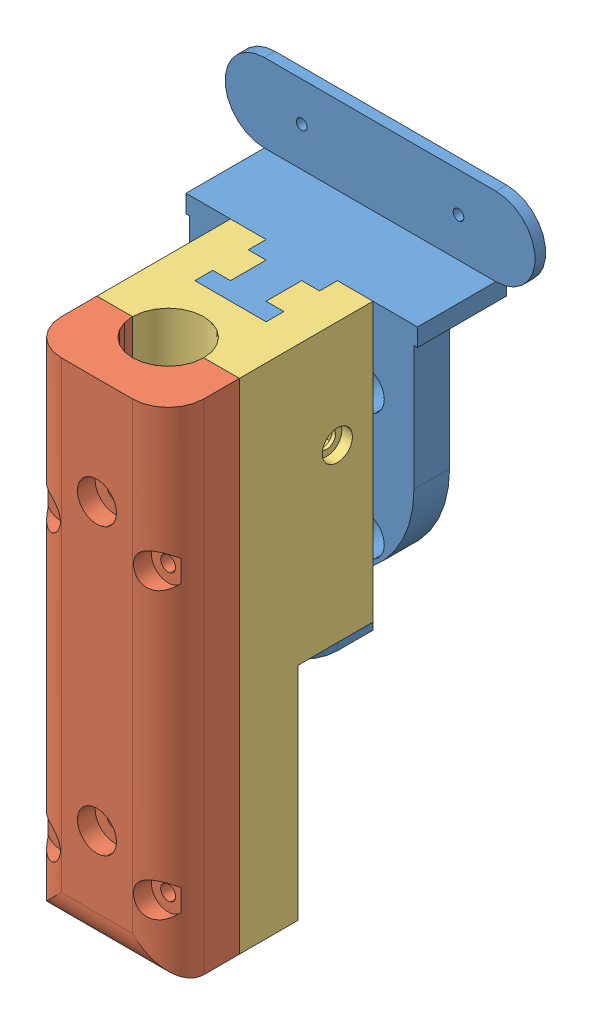
SolidWorks assembly Assem1, configuration Default. Lengths in mm.
Overall size (87 162 82.5).
3 component instances, 3 part files, 6 mates.
Components (placement in the parent):
- cameramountv3-2: cameramountv3 [Default] at (27.1037 71.5301 71.6492) size (87 102 45)
- lidmarkholder-2: lidmarkholder [Default] at (27.1037 41.5301 119.1492) size (40 140 20)
- markholderv1-2: markholderv1 [Default] at (27.1037 111.5301 81.6492) size (40 140 37.5)
Mates (geometry in assembly coordinates):
- Coincident1: coincident anti-aligned: line of cameramountv3-2 through (22.1037 86.5301 96.6492) axis (0 0 -1); line of markholderv1-2 through (22.1037 86.5301 86.6492) axis (0 0 1)
- Coincident2: coincident anti-aligned: plane of cameramountv3-2 through (27.1037 71.5301 101.6492) normal (0 0 1); plane of markholderv1-2 through (27.1037 -28.4699 101.6492) normal (0 0 -1)
- Coincident3: coincident anti-aligned: plane of cameramountv3-2 through (32.1037 33.5301 96.6492) normal (1 0 0); plane of markholderv1-2 through (32.1037 -28.4699 81.6492) normal (-1 0 0)
- Coincident4: coincident: plane of lidmarkholder-2 through (38.2991 50.5826 119.1492) normal (0 0 -1); plane of markholderv1-2 through (27.1037 -28.4699 119.1492) normal (0 0 1)
- Concentric1: concentric: circle of lidmarkholder-2; circle of markholderv1-2
- Coincident6: coincident aligned: line of lidmarkholder-2 through (47.1037 -28.4699 119.1492) axis (0 1 0); line of markholderv1-2 through (47.1037 -28.4699 119.1492) axis (0 1 0)
